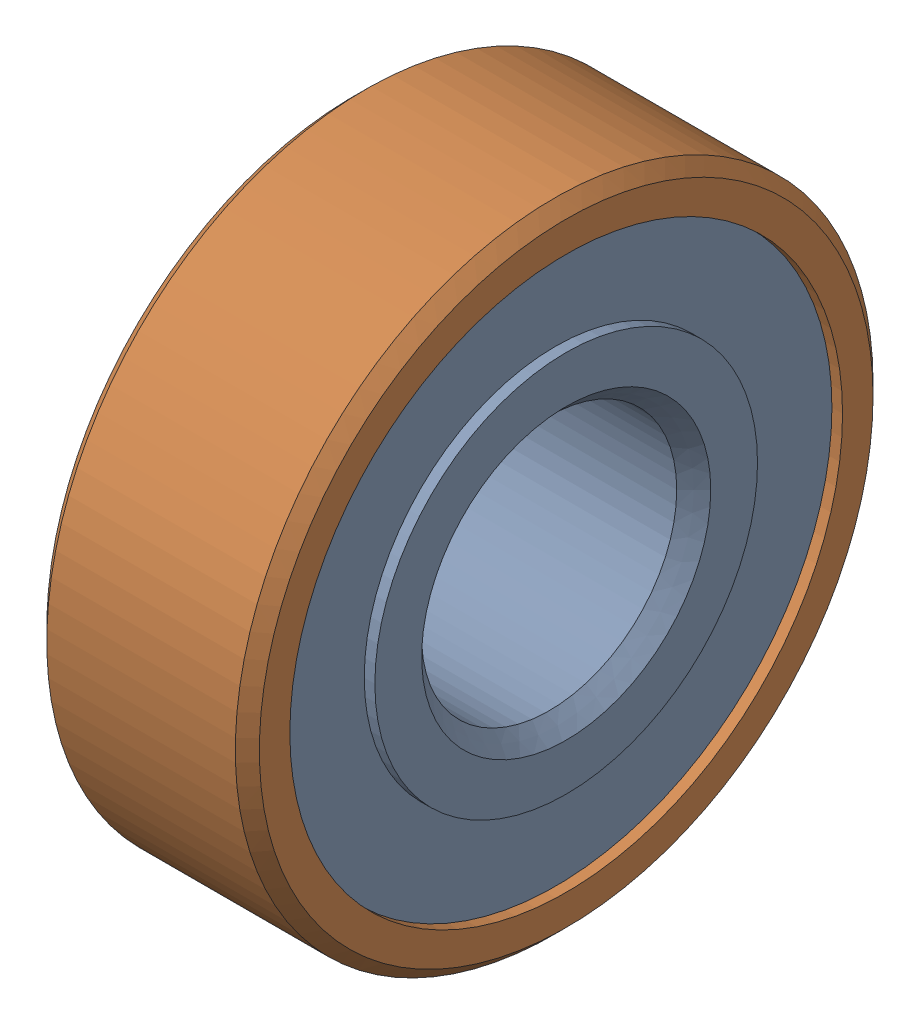
SolidWorks assembly 696ZZ, configuration Default. Lengths in mm.
Overall size (5 15 15).
13 component instances, 4 part files, 0 mates.
Components (placement in the parent):
- 696ZZ Inner ring-1: 696ZZ Inner ring [Default] at origin size (5 9 9)
- 696ZZ Outer ring-1: 696ZZ Outer ring [Default] at origin size (5 15 15)
- 696ZZ Shield-1: 696ZZ Shield [Default] at origin size (0.15 13 13)
- 696ZZ Ball-1: 696ZZ Ball [Default] at (2.5 5.25 0) x (-1 0 0) z (0 0 1) size (2 2 2)
- 696ZZ Ball-2: 696ZZ Ball [Default] at (2.5 4.0217 3.3746) x (-1 0 0) z (0 0 1) size (2 2 2)
- 696ZZ Ball-3: 696ZZ Ball [Default] at (2.5 0.9117 5.1702) x (-1 0 0) z (0 0 1) size (2 2 2)
- 696ZZ Ball-4: 696ZZ Ball [Default] at (2.5 -2.625 4.5466) x (-1 0 0) z (0 0 1) size (2 2 2)
- 696ZZ Ball-5: 696ZZ Ball [Default] at (2.5 -4.9334 1.7956) x (-1 0 0) z (0 0 1) size (2 2 2)
- 696ZZ Ball-6: 696ZZ Ball [Default] at (2.5 -4.9334 -1.7956) x (-1 0 0) z (0 0 1) size (2 2 2)
- 696ZZ Ball-7: 696ZZ Ball [Default] at (2.5 -2.625 -4.5466) x (-1 0 0) z (0 0 1) size (2 2 2)
- 696ZZ Ball-8: 696ZZ Ball [Default] at (2.5 0.9117 -5.1702) x (-1 0 0) z (0 0 1) size (2 2 2)
- 696ZZ Ball-9: 696ZZ Ball [Default] at (2.5 4.0217 -3.3746) x (-1 0 0) z (0 0 1) size (2 2 2)
- 696ZZ Shield-2: 696ZZ Shield [Default] at (5 0 0) x (-1 0 0) z (0 0 1) size (0.15 13 13)
